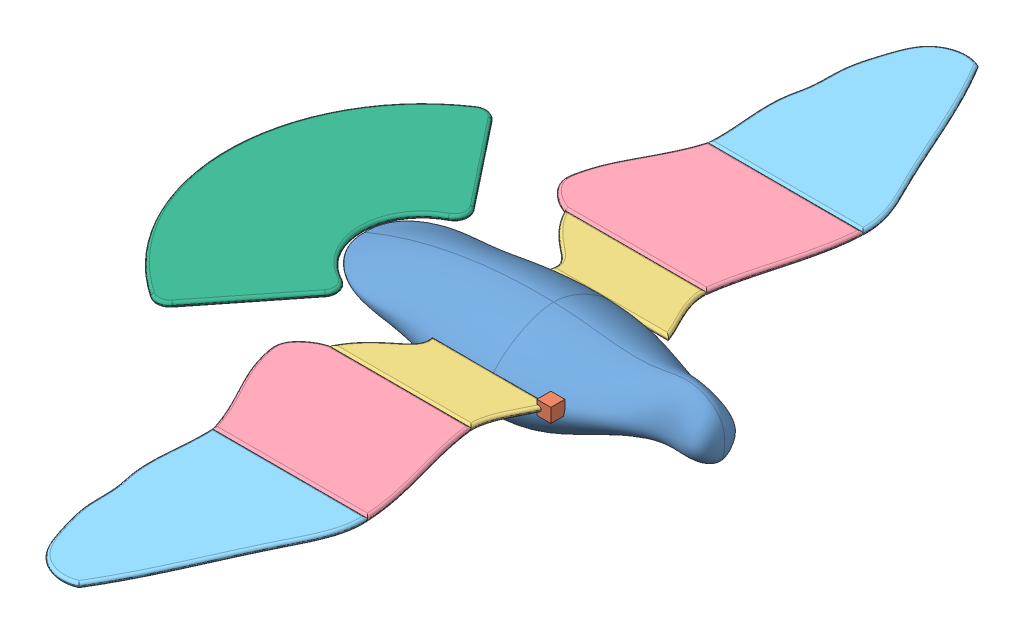
SolidWorks assembly pigeon_assembly_2, configuration Default. Lengths in mm.
Overall size (365.65 69.51 657.25).
16 component instances, 6 part files, 30 mates.
Components (placement in the parent):
- torso_contours-1: torso_contours [Default] at (-321.9795 -52 0) x (0 0 1) z (-1 0 0) size (94.74 69.51 256.9)
- ghost_component-1: ghost_component [Default] at (-81.9795 0 42) size (10 10 10) (hidden)
- ghost_component-2: ghost_component [Default] at (-81.9795 0 42) size (10 10 10) (hidden)
- upper_wing-1: upper_wing [Default] at (-217.3123 2 322.6835) x (0 0 -1) z (-1 0 0) size (42 8.51 121.5)
- ghost_component-3: ghost_component [Default] at (-97.0339 0 83.9981) size (10 10 10) (hidden)
- ghost_component-4: ghost_component [Default] at (-97.0339 0 83.9981) size (10 10 10) (hidden)
- mid_wing-1: mid_wing [Default] at (-217.3123 2 322.6835) x (0 0 -1) z (-1 0 0) size (102.24 9.28 147.46)
- hand_wing-1: hand_wing [Default] at (-217.3123 2 322.6835) x (0 0 -1) z (-1 0 0) size (157.2 28.03 132.9)
- ghost_component-5: ghost_component [Default] at (-81.9795 0 -42) size (10 10 10) (hidden)
- ghost_component-6: ghost_component [Default] at (-81.9795 0 -42) size (10 10 10) (hidden)
- upper_wing-2: upper_wing [Default] at (-217.3123 -2 -322.6835) x (0 0 1) z (-1 0 0) size (42 8.51 121.5)
- ghost_component-7: ghost_component [Default] at (-97.0339 0 -83.9981) size (10 10 10) (hidden)
- ghost_component-8: ghost_component [Default] at (-97.0339 0 -83.9981) size (10 10 10) (hidden)
- mid_wing-2: mid_wing [Default] at (-217.3123 -2 -322.6835) x (0 0 1) z (-1 0 0) size (102.24 9.28 147.46)
- hand_wing-2: hand_wing [Default] at (-217.3123 -2 -322.6835) x (0 0 1) z (-1 0 0) size (157.2 28.03 132.9)
- tail-1: tail [Default] at (-323.7845 -54 0) x (0 0 1) z (-1 0 0) size (235.93 4 125.9)
Mates (geometry in assembly coordinates):
- Coincident3: coincident anti-aligned: line of torso_contours-1 through (-269.5633 0 42) axis (1 0 0); line of ghost_component-1 through (-76.4795 0 42) axis (-1 0 0)
- Coincident4: coincident anti-aligned: plane of torso_contours-1 through (-81.9795 -52 0) normal (-1 0 0); plane of ghost_component-1 through (-81.9795 0 42) normal (1 0 0)
- Coincident5: coincident aligned: line of ghost_component-1 through (-81.9795 0 47.5) axis (0 0 -1); line of ghost_component-2 through (-81.9795 0 47.5) axis (0 0 -1)
- Coincident8: coincident aligned: line of ghost_component-2 through (-81.9795 10.5 42) axis (0 -1 0); line of upper_wing-1 through (-81.9795 0 42) axis (0 -1 0)
- Coincident9: coincident: plane of ghost_component-2 through (-81.9795 0 42) normal (0 1 0); point of upper_wing-1
- Coincident10: coincident aligned: plane of ghost_component-1 through (-81.9795 0 42) normal (0 0 1); plane of ghost_component-2 through (-81.9795 0 42) normal (0 0 1)
- Coincident11: coincident anti-aligned: line of upper_wing-1 through (-197.7314 0 83.9981) axis (1 0 0); line of ghost_component-3 through (-91.5339 0 83.9981) axis (-1 0 0)
- Coincident12: coincident: point of upper_wing-1; plane of ghost_component-3 through (-97.0339 0 83.9981) normal (1 0 0)
- Coincident13: coincident aligned: line of ghost_component-3 through (-97.0339 0 89.4981) axis (0 0 -1); line of ghost_component-4 through (-97.0339 0 89.4981) axis (0 0 -1)
- Coincident14: coincident aligned: line of ghost_component-4 through (-97.0339 10.5 83.9981) axis (0 -1 0); line of mid_wing-1 through (-97.0339 0 83.9981) axis (0 -1 0)
- Coincident15: coincident: plane of ghost_component-4 through (-97.0339 0 83.9981) normal (0 1 0); point of mid_wing-1
- Coincident16: coincident aligned: plane of ghost_component-3 through (-97.0339 0 83.9981) normal (0 0 1); plane of ghost_component-4 through (-97.0339 0 83.9981) normal (0 0 1)
- Coincident17: coincident aligned: line of mid_wing-1 through (-188.6353 0 176.9607) axis (1 0 0); line of hand_wing-1 through (-188.6353 0 176.9607) axis (1 0 0)
- Coincident18: coincident: point of mid_wing-1; point of hand_wing-1
- Coincident19: coincident anti-aligned: line of torso_contours-1 through (-269.5633 0 -42) axis (1 0 0); line of ghost_component-5 through (-76.4795 0 -42) axis (-1 0 0)
- Coincident20: coincident anti-aligned: plane of torso_contours-1 through (-81.9795 -52 0) normal (-1 0 0); plane of ghost_component-5 through (-81.9795 0 -42) normal (1 0 0)
- Coincident21: coincident aligned: line of ghost_component-5 through (-81.9795 0 -36.5) axis (0 0 -1); line of ghost_component-6 through (-81.9795 0 -36.5) axis (0 0 -1)
- Coincident22: coincident anti-aligned: line of ghost_component-6 through (-76.4795 0 -42) axis (-1 0 0); line of upper_wing-2 through (-166.7932 0 -42) axis (1 0 0)
- Coincident23: coincident: plane of ghost_component-6 through (-81.9795 0 -42) normal (1 0 0); point of upper_wing-2
- Coincident24: coincident aligned: plane of ghost_component-5 through (-81.9795 0 -42) normal (0 0 1); plane of ghost_component-6 through (-81.9795 0 -42) normal (0 0 1)
- Coincident25: coincident anti-aligned: line of upper_wing-2 through (-197.7314 0 -83.9981) axis (1 0 0); line of ghost_component-7 through (-91.5339 0 -83.9981) axis (-1 0 0)
- Coincident26: coincident: point of upper_wing-2; plane of ghost_component-7 through (-97.0339 0 -83.9981) normal (1 0 0)
- Coincident27: coincident aligned: line of ghost_component-7 through (-97.0339 0 -78.4981) axis (0 0 -1); line of ghost_component-8 through (-97.0339 0 -78.4981) axis (0 0 -1)
- Coincident28: coincident anti-aligned: line of ghost_component-8 through (-97.0339 10.5 -83.9981) axis (0 -1 0); line of mid_wing-2 through (-97.0339 0 -83.9981) axis (0 1 0)
- Coincident29: coincident: plane of ghost_component-8 through (-97.0339 0 -83.9981) normal (0 1 0); point of mid_wing-2
- Coincident30: coincident aligned: plane of ghost_component-7 through (-97.0339 0 -83.9981) normal (0 0 1); plane of ghost_component-8 through (-97.0339 0 -83.9981) normal (0 0 1)
- Coincident31: coincident aligned: line of mid_wing-2 through (-188.6353 0 -176.9607) axis (1 0 0); line of hand_wing-2 through (-188.6353 0 -176.9607) axis (1 0 0)
- Coincident32: coincident: point of mid_wing-2; point of hand_wing-2
- Coincident33: coincident aligned: line of torso_contours-1 through (-229.9795 0 -52.1057) axis (0 0 1); line of tail-1 through (-229.9795 0 -44.8451) axis (0 0 1)
- Coincident34: coincident aligned: plane of torso_contours-1 through (-256.6828 0 0) normal (0 0 1); plane of tail-1 through (-258.4878 0 0) normal (0 0 1)
